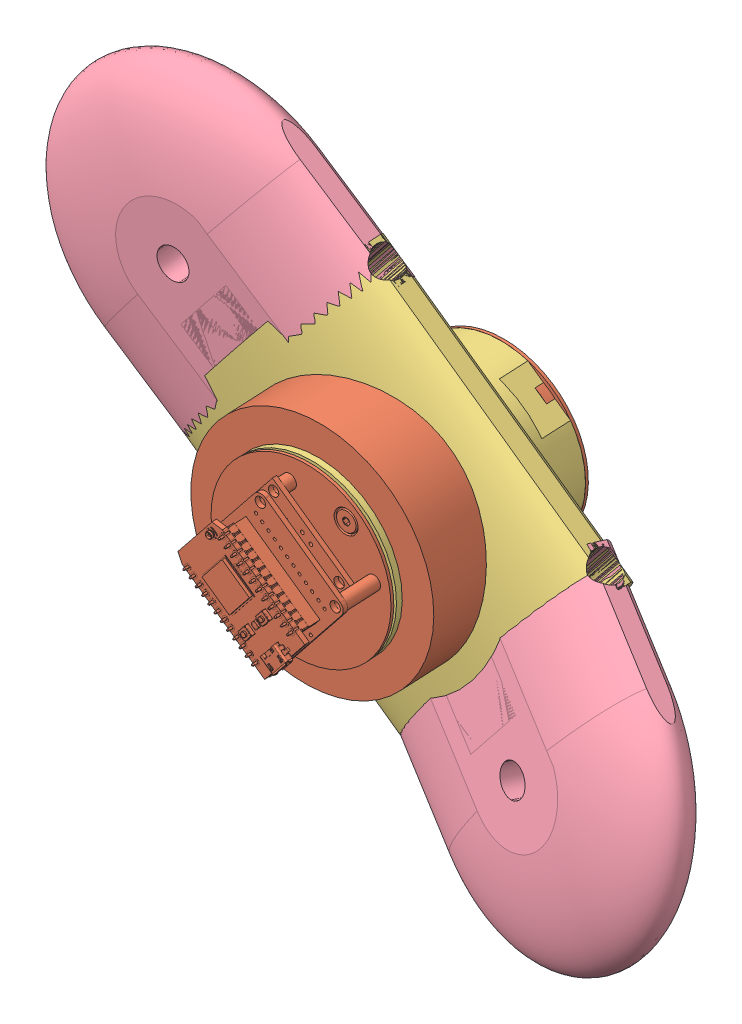
SolidWorks assembly robo_leg_link, configuration Default. Lengths in mm.
Overall size (261.59 235.54 102.93).
5 component instances, 4 part files, 14 mates.
Components (placement in the parent):
- leg-1: leg [Default] at (97.1408 47.1972 -11.6778) x (-0.366689 -0.411393 -0.834443) z (-0.78315 0.620661 0.038153) size (28.15 17.14 8)
- single_bot1-1: single_bot1 [Default] at (165.3852 126.9548 -147.944) x (0.99959 0.001787 0.028569) z (-0.028602 0.022562 0.999336) size (79.61 77.63 98.49)
- link1-1: link1 [Default] at (96.1435 53.6643 49.4201) x (0.61941 0.78404 -0.040144) z (-0.78315 0.620661 0.038153) size (98.86 67 101.6)
- link2-1: link2 [Default] at (100.5662 46.1573 -28.9567) x (0.61941 0.78404 -0.040144) z (0.767343 -0.59383 0.241971) size (100 28.27 88.1)
- link2-2: link2 [Default] at (96.7581 53.1166 48.2054) x (0.61941 0.78404 -0.040144) z (-0.781433 0.620651 0.064461) size (100 28.27 88.1)
Mates (geometry in assembly coordinates):
- Concentric2: concentric anti-aligned: cylinder of leg-1 through (97.1408 47.1972 -11.6778) axis (-0.78315 0.620661 0.038153) radius 1.575; cylinder of single_bot1-1 through (90.8756 52.1625 -11.3726) axis (0.78315 -0.620661 -0.038153) radius 1.5
- Coincident4: coincident anti-aligned: plane of single_bot1-1 through (52.3777 48.4711 -15.2389) normal (0.05483 0.007806 0.998465); plane of link1-1 through (92.4699 53.1413 -17.477) normal (-0.05483 -0.007806 -0.998465)
- Parallel3: parallel anti-aligned: plane of single_bot1-1 through (69.083 45.1918 36.2598) normal (-0.61941 -0.78404 0.040144); plane of link1-1 through (95.8519 85.6879 -7.7016) normal (0.61941 0.78404 -0.040144)
- Coincident7: coincident anti-aligned: plane of leg-1 through (90.8756 52.1625 -11.3726) normal (-0.78315 0.620661 0.038153); plane of single_bot1-1 through (89.5264 50.578 -13.2902) normal (0.78315 -0.620661 -0.038153)
- Lock2: lock: unknown of single_bot1-1; unknown of link1-1
- Concentric4: concentric anti-aligned: cylinder of single_bot1-1 through (96.1956 53.6717 50.3687) axis (-0.05483 -0.007806 -0.998465) radius 27.3625; cylinder of link1-1 through (92.4699 53.1413 -17.477) axis (0.05483 0.007806 0.998465) radius 28.575
- Parallel4: parallel anti-aligned: plane of single_bot1-1 through (54.3217 54.2886 52.6633) normal (-0.05483 -0.007806 -0.998465); plane of link1-1 through (96.1435 53.6643 49.4201) normal (0.05483 0.007806 0.998465)
- Concentric5: concentric aligned: cylinder of single_bot1-1 through (92.4699 53.1413 -17.477) axis (0.05483 0.007806 0.998465) radius 27.3625; cylinder of link1-1 through (92.4699 53.1413 -17.477) axis (0.05483 0.007806 0.998465) radius 28.575
- Concentric6: concentric aligned: cylinder of link1-1 through (99.7574 131.9538 15.0581) axis (-0.61941 -0.78404 0.040144) radius 5; cylinder of link2-2 through (111.5262 146.8506 14.2953) axis (-0.61941 -0.78404 0.040144) radius 5
- Concentric7: concentric aligned: cylinder of link1-1 through (169.3794 76.777 11.6662) axis (-0.61941 -0.78404 0.040144) radius 5; cylinder of link2-1 through (181.1482 91.6738 10.9035) axis (-0.61941 -0.78404 0.040144) radius 5
- Coincident9: coincident aligned: plane of link1-1 through (112.1549 -21.4968 49.1285) normal (-0.61941 -0.78404 0.040144); plane of link2-2 through (-25.8802 87.9975 57.7854) normal (-0.61941 -0.78404 0.040144)
- Coincident10: coincident aligned: plane of link1-1 through (112.1549 -21.4968 49.1285) normal (-0.61941 -0.78404 0.040144); plane of link2-1 through (160.8383 -62.392 1.5872) normal (-0.61941 -0.78404 0.040144)
- Coincident11: coincident aligned: plane of link1-1 through (172.8571 55.3392 45.1944) normal (0.61941 0.78404 -0.040144); plane of link2-1 through (221.5405 14.4439 -2.3469) normal (0.61941 0.78404 -0.040144)
- Coincident12: coincident aligned: plane of link1-1 through (172.8571 55.3392 45.1944) normal (0.61941 0.78404 -0.040144); plane of link2-2 through (34.822 164.8334 53.8512) normal (0.61941 0.78404 -0.040144)
